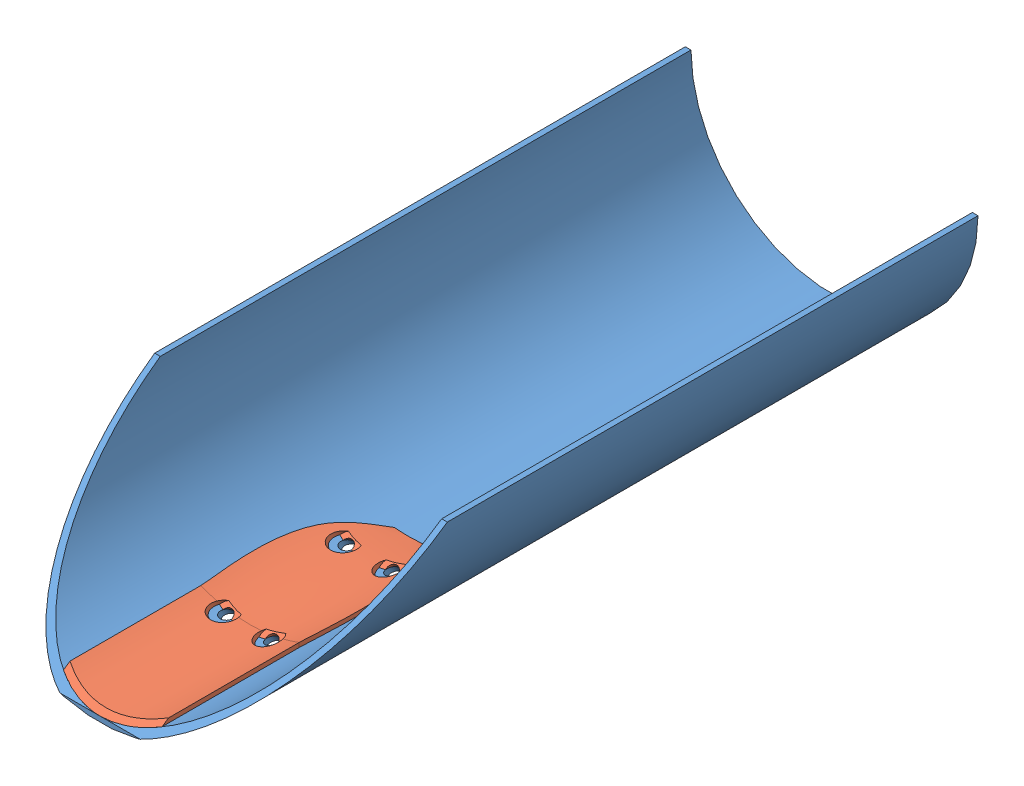
SolidWorks assembly BoltGuardAssembly, configuration Default. Lengths in mm.
Overall size (104 52 260).
3 component instances, 3 part files, 8 mates.
Components (placement in the parent):
- Funnel Drill Guide-1: Funnel Drill Guide [Default] at (-48.8552 29.2771 -114.8175) size (31.31 9.01 109.06) (hidden)
- Part2^BoltGuardAssembly-1: Part2^BoltGuardAssembly [Default] at (-48.8552 29.2771 46.3907) x (-1 0 0) z (0 0 -1) size (104 52 260) (virtual)
- BoltGuard-1: BoltGuard [Default] at (-48.8552 29.2771 46.3907) size (74.69 51.38 260)
Mates (geometry in assembly coordinates):
- InPlace1: in place: plane of Funnel Drill Guide-1 through (-48.8552 93.5754 46.3907) normal (0 0 -1); plane of ? through (0 0 46.3907) normal (0 0 -1); moOrthogonalPlaneRef_w of Funnel Drill Guide-1 through (-48.8552 93.5754 46.3907) normal (0 0 -1); plane of ? through (0 0 46.3907) normal (0 1 0); plane of Funnel Drill Guide-1 through (-48.8552 93.5754 46.3907) normal (0 0 -1); plane of ? through (0 0 46.3907) normal (-1 0 0); plane of Funnel Drill Guide-1 through (-48.8552 93.5754 46.3907) normal (0 0 -1); unknown of Part2^BoltGuardAssembly-1
- Coincident1: coincident: plane of Funnel Drill Guide-1; plane of Part2^BoltGuardAssembly-1
- Coincident2: coincident: moOrthogonalPlaneRef_w of Funnel Drill Guide-1 through (-48.8552 29.2771 46.3907) normal (0 1 0); plane of Part2^BoltGuardAssembly-1 through (-48.8552 29.2771 46.3907) normal (0 1 0)
- Coincident3: coincident: moOrthogonalPlaneRef_w of Funnel Drill Guide-1 through (-48.8552 29.2771 46.3907) normal (1 0 0); plane of Part2^BoltGuardAssembly-1 through (-48.8552 29.2771 46.3907) normal (-1 0 0)
- InPlace2: in place: plane of Part2^BoltGuardAssembly-1 through (-48.8552 93.5754 46.3907) normal (0 0 1); plane of ? through (0 0 46.3907) normal (0 0 1); plane of Part2^BoltGuardAssembly-1 through (-48.8552 93.5754 46.3907) normal (0 0 1); plane of ? through (0 0 46.3907) normal (0 1 0); plane of Part2^BoltGuardAssembly-1 through (-48.8552 93.5754 46.3907) normal (0 0 1); plane of ? through (0 0 46.3907) normal (1 0 0); plane of Part2^BoltGuardAssembly-1 through (-48.8552 93.5754 46.3907) normal (0 0 1); unknown of BoltGuard-1
- Coincident4: coincident: plane of Part2^BoltGuardAssembly-1; plane of BoltGuard-1
- Coincident5: coincident: moOrthogonalPlaneRef_w of Part2^BoltGuardAssembly-1 through (-48.8552 29.2771 46.3907) normal (0 1 0); plane of BoltGuard-1 through (-48.8552 29.2771 46.3907) normal (0 1 0)
- Coincident6: coincident: moOrthogonalPlaneRef_w of Part2^BoltGuardAssembly-1 through (-48.8552 29.2771 46.3907) normal (-1 0 0); plane of BoltGuard-1 through (-48.8552 29.2771 46.3907) normal (1 0 0)
